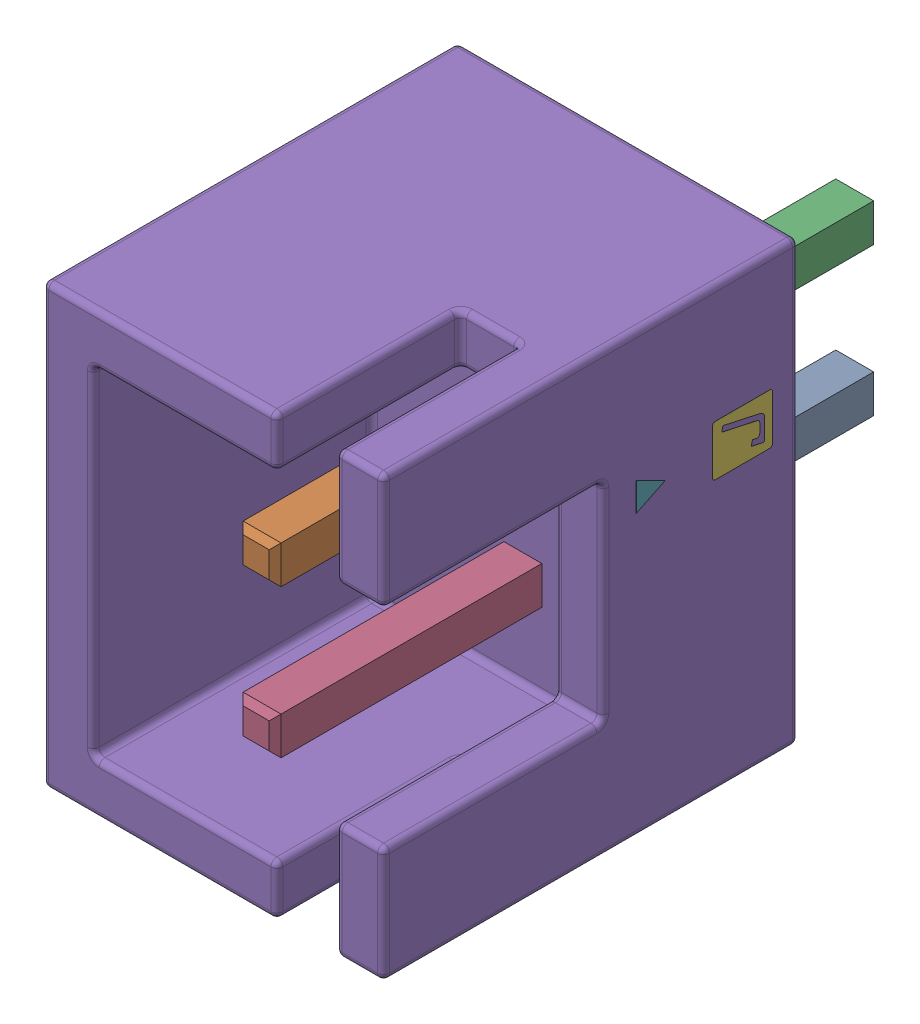
SolidWorks assembly input.step, configuration Default. Lengths in mm.
Overall size (5.75 7.4 10.4).
5 component instances, 3 part files, 0 mates.
Components (placement in the parent):
- Conn_JST_B2B-XH-A_LF_SN_eec.step-1: Conn_JST_B2B-XH-A_LF_SN_eec.step [Default] at (6.841 22.499 0) x (0 -1 0) z (0 0 1) size (7.4 5.75 10.4)
  - 1-0.step-1: 1-0.step [Default] at (0 0.025 0) x (-1 0 0) z (0 1 0) size (7.4 10.4 5.75)
    - 1-1.step-1: 1-1.step [Default] at origin size (3.14 10.2 0.64)
    - B2B-XH-A.step-1: B2B-XH-A.step [Default] at origin size (7.4 7 5.75)
    - JST_Logo_adjustable.step-1: JST_Logo_adjustable.step [Default] at (-1.7267 5.5034 2.841) size (0.85 2.3 0.01)
